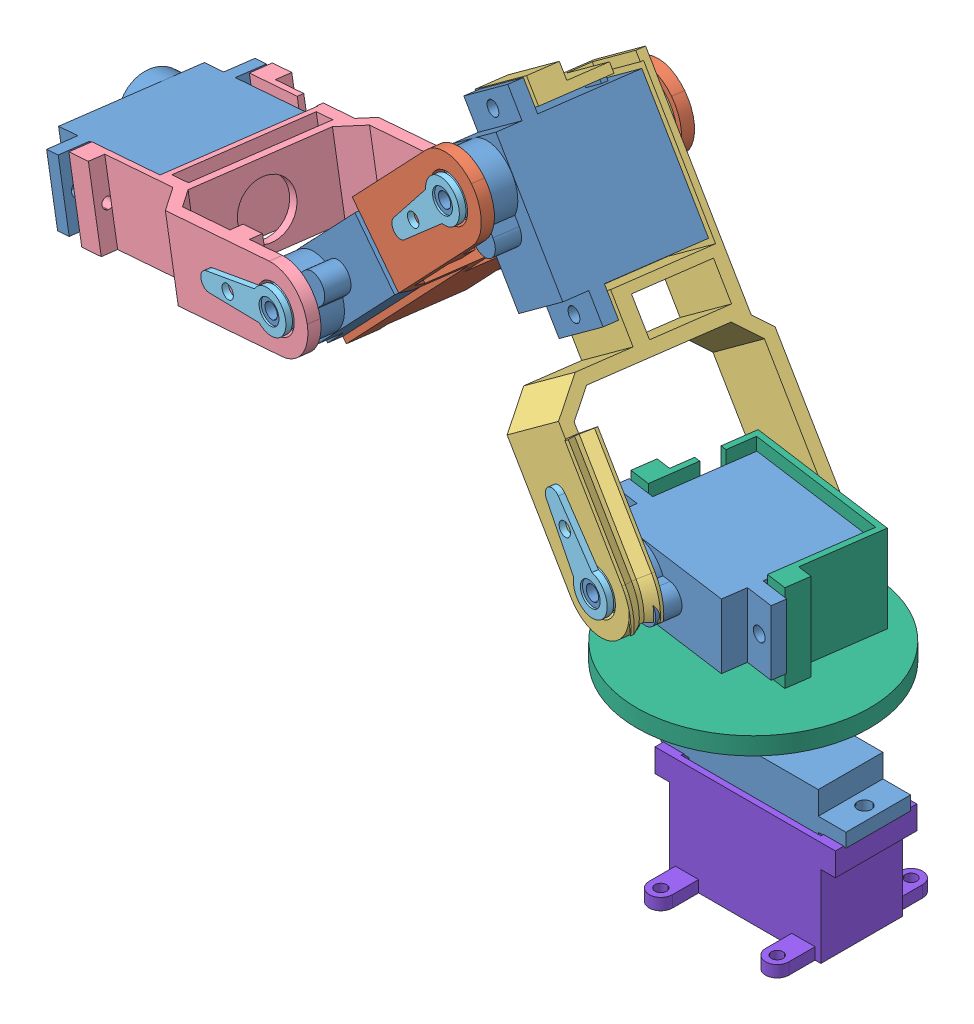
SolidWorks assembly Sestava1, configuration základní. Lengths in mm.
Overall size (158.96 97.57 59.8).
14 component instances, 8 part files, 37 mates.
Components (placement in the parent):
- servo9g_ARM_2-1: servo9g_ARM_2 [zakladni] at (-76.0387 49.2974 -23.9435) x (0.687799 0.719621 0.095274) z (-0.13721 0 0.990542) size (31.75 11.11 29.23)
- servo9g_ARM_2-2: servo9g_ARM_2 [zakladni] at (-41.5372 77.675 -18.8363) x (0.598824 -0.796574 0.082949) z (-0.13721 0 0.990542) size (31.75 11.11 29.23)
- servo9g_ARM_2-3: servo9g_ARM_2 [zakladni] x (1 0 0) z (0 1 0) size (31.75 11.11 29.23)
- servo9g_ARM_2-4: servo9g_ARM_2 [zakladni] at (-8.9666 41.2249 -13.4917) x (0.990542 0 0.13721) z (-0.13721 0 0.990542) size (31.75 11.11 29.23)
- servo9g_ARM_2-5: servo9g_ARM_2 [zakladni] at (-110.1389 39.5307 -17.6513) x (-0.13721 0 0.990542) z (-0.970643 -0.199436 -0.134454) size (31.75 11.11 29.23)
- ARM___2-1: ARM___2 [Výchozí] at (-58.1617 60.3737 -8.7217) x (-0.687799 -0.719621 -0.095274) z (0.13721 0 -0.990542) size (67.75 13 33.5)
- ARM__spring-1: ARM__spring [Výchozí] at (-35.4714 56.4132 -4.9981) x (-0.598824 0.796574 -0.082949) z (0.13721 0 -0.990542) size (68 15.35 35.5)
- ARM_FRONT_2-1: ARM_FRONT_2 [Výchozí] at (-103.2106 34.304 -15.2899) x (-0.970643 -0.199436 -0.134454) z (0.13721 0 -0.990542) size (50.25 13 32.92)
- paka_arm-1: paka_arm [Výchozí] at (-83.8088 45.41 4.8123) x (0.970643 0.199436 0.134454) z (-0.197549 0.979911 -0.027365) size (17.4 4 6.8)
- paka_arm-2: paka_arm [Výchozí] at (-48.8266 81.9781 9.9861) x (0.687799 0.719621 0.095274) z (-0.712815 0.694367 -0.098739) size (17.4 4 6.8)
- swing_2-1: swing_2 [Výchozí] at (-8.1593 33.225 -16.5347) x (-0.13721 0 0.990542) z (-0.990542 0 -0.13721) size (40 18 40.67)
- paka_arm-3: paka_arm [Výchozí] at (-18.3721 41.2249 15.0376) x (0.598824 -0.796574 0.082949) z (0.78904 0.604541 0.109298) size (17.4 4 6.8)
- paka_3-1: paka_3 [Výchozí] at (-5.402 30.225 0) x (0.838876 0 -0.544323) z (-0.544323 0 -0.838876) size (27.61 4 27.61)
- ARM_footer-1: ARM_footer [Výchozí] at (1.3884 -10 7) x (0 1 0) z (-1 0 0) size (18 27 31)
Mates (geometry in assembly coordinates):
- Sjednocená1: coincident anti-aligned: plane of servo9g_ARM_2-1 through (-72.0791 45.4402 -23.395) normal (0.712815 -0.694367 0.098739); plane of ARM___2-1 through (-58.8745 61.0681 -8.8204) normal (-0.712815 0.694367 -0.098739)
- Sjednocená2: coincident anti-aligned: plane of servo9g_ARM_2-1 through (-74.3843 61.3074 -7.6878) normal (0.13721 0 -0.990542); plane of ARM___2-1 through (-122.9648 70.9545 -14.4172) normal (-0.13721 0 0.990542)
- Vystředění1: width aligned: plane of servo9g_ARM_2-1 through (-89.6707 45.3139 -9.8053) normal (-0.687799 -0.719621 -0.095274); plane of servo9g_ARM_2-1 through (-74.7111 61.3074 -5.3291) normal (0.687799 0.719621 0.095274); plane of ARM___2-1 through (-65.8545 54.2317 -6.5062) normal (-0.687799 -0.719621 -0.095274); plane of ARM___2-1 through (-82.3617 36.9608 -8.7928) normal (0.687799 0.719621 0.095274)
- Soustředná1: concentric aligned: cylinder of ARM___2-1 through (-43.8184 81.9781 -26.1686) axis (-0.13721 0 0.990542) radius 4.75; cylinder of ARM__spring-1 through (-44.1375 81.9781 -23.8656) axis (-0.13721 0 0.990542) radius 4.5
- Sjednocená4: coincident anti-aligned: plane of servo9g_ARM_2-2 through (-45.9203 74.3168 -19.4434) normal (-0.78904 -0.604541 -0.109298); plane of ARM__spring-1 through (-34.6824 57.0177 -4.8888) normal (0.78904 0.604541 0.109298)
- Sjednocená5: coincident anti-aligned: plane of servo9g_ARM_2-2 through (-48.7088 93.5061 -3.8031) normal (0.13721 0 -0.990542); plane of ARM__spring-1 through (-15.4706 119.1293 0.8011) normal (-0.13721 0 0.990542)
- Vystředění2: width anti-aligned: plane of ARM__spring-1 through (-55.1546 83.703 -4.696) normal (0.598824 -0.796574 0.082949); plane of ARM__spring-1 through (-40.7828 64.5852 -2.7052) normal (-0.598824 0.796574 -0.082949); plane of servo9g_ARM_2-2 through (-45.8569 89.7124 -3.4081) normal (-0.598824 0.796574 -0.082949); plane of servo9g_ARM_2-2 through (-30.3698 72.0086 -17.2894) normal (0.598824 -0.796574 0.082949)
- Vystředění3: width anti-aligned: plane of ARM___2-1 through (-63.2377 71.7393 -23.8108) normal (-0.13721 0 0.990542); plane of ARM___2-1 through (-67.1482 71.7393 4.4196) normal (0.13721 0 -0.990542); plane of ARM__spring-1 through (-44.5491 81.9781 -20.894) normal (0.13721 0 -0.990542); plane of servo9g_ARM_2-2 through (-45.1356 77.675 7.1407) normal (-0.13721 0 0.990542)
- Soustředná2: concentric anti-aligned: cylinder of servo9g_ARM_2-1 through (-83.3526 45.41 1.5188) axis (0.13721 0 -0.990542) radius 5.5; circle of ARM_FRONT_2-1
- Vystředění4: width anti-aligned: plane of servo9g_ARM_2-1 through (-79.6371 49.2974 2.0334) normal (-0.13721 0 0.990542); plane of ARM___2-1 through (-79.5313 45.41 -26.0678) normal (0.13721 0 -0.990542); plane of ARM_FRONT_2-1 through (-74.1871 53.0758 -27.6748) normal (0.13721 0 -0.990542); plane of ARM_FRONT_2-1 through (-78.6465 53.0758 4.5178) normal (-0.13721 0 0.990542)
- Soustředná3: concentric anti-aligned: cylinder of servo9g_ARM_2-1 through (-83.7642 45.41 4.4904) axis (0.13721 0 -0.990542) radius 2.0388; cylinder of paka_arm-1 through (-83.6716 45.41 3.8218) axis (-0.13721 0 0.990542) radius 2
- Soustředná4: concentric anti-aligned: cylinder of servo9g_ARM_2-2 through (-48.782 81.9781 9.6642) axis (0.13721 0 -0.990542) radius 2.0388; cylinder of paka_arm-2 through (-48.6894 81.9781 8.9956) axis (-0.13721 0 0.990542) radius 2
- Sjednocená6: coincident: plane of ARM___2-1 through (-48.852 91.169 8.9731) normal (-0.13721 0 0.990542); line of paka_arm-2 through (-58.4352 73.9347 7.6456) axis (0.62857 0.772864 0.08707)
- Sjednocená7: coincident: plane of ARM_FRONT_2-1 through (-78.6465 53.0758 4.5178) normal (-0.13721 0 0.990542); line of paka_arm-1 through (-96.2165 44.3583 2.084) axis (0.951728 0.277189 0.131834)
- Rovnoběžná1: parallel aligned: plane of ARM_FRONT_2-1 through (-105.7787 47.0428 -15.6457) normal (-0.197549 0.979911 -0.027365); plane of paka_arm-1 through (-83.8088 45.41 4.8123) normal (-0.197549 0.979911 -0.027365)
- Rovnoběžná3: parallel aligned: plane of ARM___2-1 through (-67.4283 69.4005 -10.0053) normal (-0.712815 0.694367 -0.098739); plane of paka_arm-2 through (-48.8266 81.9781 9.9861) normal (-0.712815 0.694367 -0.098739)
- Sjednocená11: coincident anti-aligned: plane of servo9g_ARM_2-5 through (-109.0415 34.0873 -17.4993) normal (0.197549 -0.979911 0.027365); plane of ARM_FRONT_2-1 through (-103.4082 35.2839 -15.3173) normal (-0.197549 0.979911 -0.027365)
- Sjednocená12: coincident anti-aligned: plane of servo9g_ARM_2-5 through (-109.7413 44.9741 -28.5959) normal (0.970643 0.199436 0.134454); plane of ARM_FRONT_2-1 through (-110.7178 34.0873 -5.398) normal (-0.970643 -0.199436 -0.134454)
- Vystředění5: width anti-aligned: plane of servo9g_ARM_2-5 through (-112.7908 44.9741 -6.5812) normal (-0.13721 0 0.990542); plane of servo9g_ARM_2-5 through (-125.1502 41.8081 -30.7304) normal (0.13721 0 -0.990542); plane of ARM_FRONT_2-1 through (-124.3068 31.2952 -7.2804) normal (0.13721 0 -0.990542); plane of ARM_FRONT_2-1 through (-121.0137 31.2952 -31.0534) normal (-0.13721 0 0.990542)
- Sjednocená14: coincident anti-aligned: plane of servo9g_ARM_2-4 through (0.0774 46.7799 3.7876) normal (0.13721 0 -0.990542); plane of swing_2-1 through (-23.8133 80.0443 0.4783) normal (-0.13721 0 0.990542)
- Soustředná5: concentric anti-aligned: cylinder of servo9g_ARM_2-4 through (-17.9158 41.2249 11.744) axis (0.13721 0 -0.990542) radius 5.5; cylinder of ARM__spring-1 through (-13.2953 41.2249 -21.6125) axis (-0.13721 0 0.990542) radius 4.75
- Soustředná8: concentric aligned: cylinder of servo9g_ARM_2-4 through (5.2651 41.225 -16.3094) axis (-0.13721 0 0.990542) radius 1.1906; cylinder of swing_2-1 through (2.9849 41.225 0.1522) axis (-0.13721 0 0.990542) radius 0.9
- Rovnoběžná5: parallel aligned: plane of servo9g_ARM_2-4 through (-8.9666 46.7799 -13.4917) normal (0 1 0); plane of swing_2-1 through (-8.1593 48.225 -16.5347) normal (0 1 0)
- Vystředění8: width anti-aligned: plane of ARM__spring-1 through (-9.2137 39.9767 15.2967) normal (-0.13721 0 0.990542); plane of ARM__spring-1 through (-4.6858 39.9767 -17.3912) normal (0.13721 0 -0.990542); plane of swing_2-1 through (-14.0259 41.2249 -16.3378) normal (0.13721 0 -0.990542); plane of servo9g_ARM_2-4 through (-12.5649 41.2249 12.4853) normal (-0.13721 0 0.990542)
- Soustředná9: concentric anti-aligned: cylinder of servo9g_ARM_2-4 through (-18.3275 41.2249 14.7157) axis (0.13721 0 -0.990542) radius 2.0388; cylinder of paka_arm-3 through (-17.8232 41.2249 11.0754) axis (-0.13721 0 0.990542) radius 3
- Sjednocená17: coincident: plane of ARM__spring-1 through (-9.2137 39.9767 15.2967) normal (-0.13721 0 0.990542); line of paka_arm-3 through (-24.6122 52.1816 13.1637) axis (0.660027 -0.745657 0.091427)
- Rovnoběžná7: parallel aligned: plane of ARM__spring-1 through (-25.2139 64.2722 -3.5772) normal (0.78904 0.604541 0.109298); plane of paka_arm-3 through (-18.3721 41.2249 15.0376) normal (0.78904 0.604541 0.109298)
- Sjednocená19: coincident anti-aligned: plane of swing_2-1 through (-5.402 30.225 0) normal (0 -1 0); plane of paka_3-1 through (-15.8879 30.225 6.804) normal (0 1 0)
- Soustředná10: concentric aligned: cylinder of swing_2-1 through (-5.402 30.225 0) axis (0 1 0) radius 20; cylinder of paka_3-1 through (-5.402 26.225 0) axis (0 1 0) radius 3
- Soustředná11: concentric anti-aligned: cylinder of servo9g_ARM_2-3 through (-5.402 29.225 0) axis (0 -1 0) radius 2.0388; cylinder of paka_3-1 through (-5.402 26.225 0) axis (0 1 0) radius 3
- Sjednocená20: coincident anti-aligned: plane of servo9g_ARM_2-3 through (0 26.225 0) normal (0 1 0); plane of paka_3-1 through (-5.402 26.225 0) normal (0 -1 0)
- Sjednocená21: coincident aligned: plane of servo9g_ARM_2-3 through (0 0 0) normal (0 1 0); plane of assembly through (0 0 0) normal (0 1 0)
- Sjednocená22: coincident anti-aligned: plane of servo9g_ARM_2-3 through (0 0 0) normal (0 0 -1); plane of assembly through (0 0 0) normal (0 0 1)
- Sjednocená23: coincident aligned: plane of servo9g_ARM_2-3; plane of assembly through (0 0 0) normal (1 0 0)
- Sjednocená24: coincident anti-aligned: plane of servo9g_ARM_2-3 through (-10.8956 0 -5.555) normal (0 -1 0); plane of ARM_footer-1 through (12.2168 0 6) normal (0 1 0)
- Vystředění9: width anti-aligned: plane of servo9g_ARM_2-3 through (0 0 5.555) normal (0 0 1); plane of servo9g_ARM_2-3 through (0 0 -5.555) normal (0 0 -1); plane of ARM_footer-1 through (1.3884 -10 6) normal (0 0 -1); plane of ARM_footer-1 through (1.3884 -10 -6) normal (0 0 1)
- Vystředění10: width aligned: plane of ARM_footer-1 through (-12.7832 -10.3431 -43.013) normal (-1 0 0); plane of ARM_footer-1 through (13.2169 -8 -43.013) normal (1 0 0); plane of servo9g_ARM_2-3 through (-10.8956 15.875 -5.555) normal (-1 0 0); plane of servo9g_ARM_2-3 through (11.3293 0 -5.555) normal (1 0 0)
